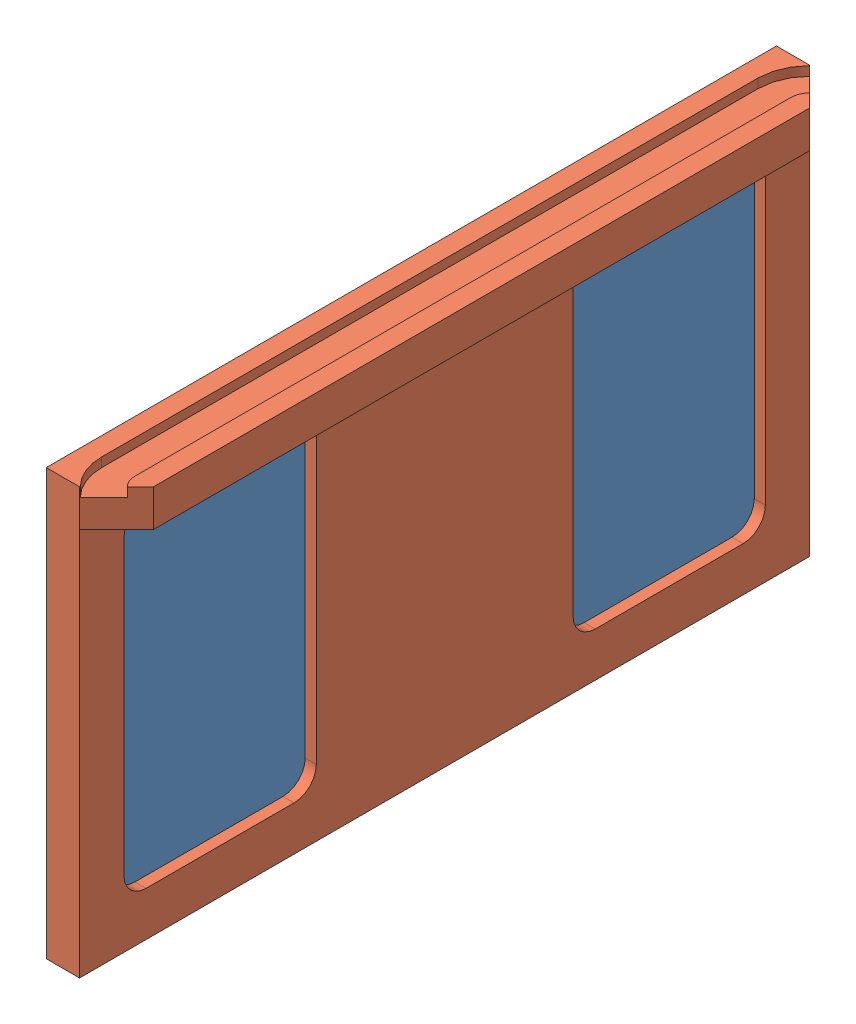
SolidWorks assembly rear_plate_assembly, configuration Default. Lengths in mm.
Overall size (19 115 197.4).
3 component instances, 2 part files, 4 mates.
Components (placement in the parent):
- front_window_large-1: front_window_large [Default] at (-269.35 -19.485 0) x (0 0 -1) z (1 0 0) size (68 107 6)
- front_window_large-2: front_window_large [Default] at (-269.35 -19.485 -121.4) x (0 0 -1) z (1 0 0) size (68 107 6)
- rear_plate-1: rear_plate [Default] at (-260.35 -19.485 0) x (0 0 1) z (-1 0 0) size (197.4 115 19)
Mates (geometry in assembly coordinates):
- Coincident122: coincident anti-aligned: plane of rear_plate-1 through (-263.35 39.5 80.7) normal (-1 0 0); plane of front_window_large-1 through (-263.35 39.5 80.7) normal (1 0 0)
- Concentric6: concentric aligned: cylinder of rear_plate-1 through (-263.35 -39.5 80.7) axis (-1 0 0) radius 14; cylinder of front_window_large-1 through (-263.35 -39.5 80.7) axis (-1 0 0) radius 14
- Coincident121: coincident anti-aligned: plane of rear_plate-1 through (-263.35 39.5 -80.7) normal (-1 0 0); plane of front_window_large-2 through (-263.35 39.5 -40.7) normal (1 0 0)
- Concentric5: concentric aligned: cylinder of rear_plate-1 through (-263.35 -39.5 -40.7) axis (-1 0 0) radius 14; cylinder of front_window_large-2 through (-263.35 -39.5 -40.7) axis (-1 0 0) radius 14
